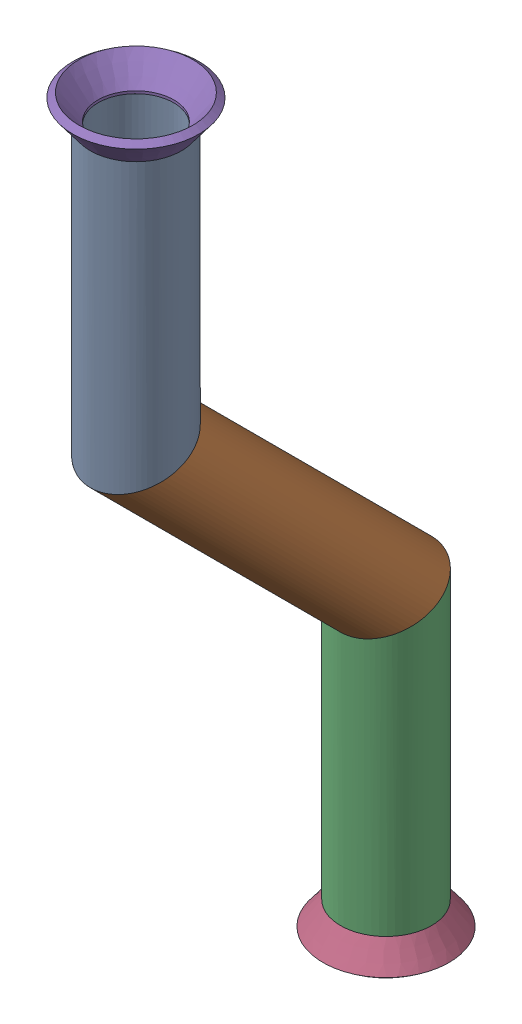
SolidWorks assembly Pipe 2, configuration Default. Lengths in mm.
Overall size (17.7 118.89 52.61).
3 component instances, 2 part files, 4 mates.
Components (placement in the parent):
- Part6-1: Part6 [Default<As Machined>] at origin size (12.7 111.11 47.61)
- Flared pipe end - .5 inch-1: Flared pipe end - .5 inch [Default<As Machined>] at (0 -546.4518 327.8546) x (0.999982 0 0.006039) z (0 -1 0) size (17.59 17.59 3.89)
- Flared pipe end - .5 inch-2: Flared pipe end - .5 inch [Default<As Machined>] at (0 -435.3411 362.7653) x (0.999982 0 -0.006039) z (0 1 0) size (17.59 17.59 3.89)
Mates (geometry in assembly coordinates):
- Coincident1015: coincident: plane of Part6-1 through (0 -546.4518 327.8546) normal (0 -1 0); plane of Flared pipe end - .5 inch-1 through (-0.0319 -546.4518 333.1377) normal (0 1 0)
- Concentric653: concentric: circle of Part6-1; circle of Flared pipe end - .5 inch-1
- Coincident1012: coincident: plane of Part6-1 through (0 -435.3411 362.7653) normal (0 1 0); plane of Flared pipe end - .5 inch-2 through (-0.0319 -435.3411 357.4822) normal (0 -1 0)
- Coincident1014: coincident: plane of Part6-1 through (0 -435.3411 362.7653) normal (0 1 0); plane of Flared pipe end - .5 inch-2 through (-0.0319 -435.3411 357.4822) normal (0 -1 0)
